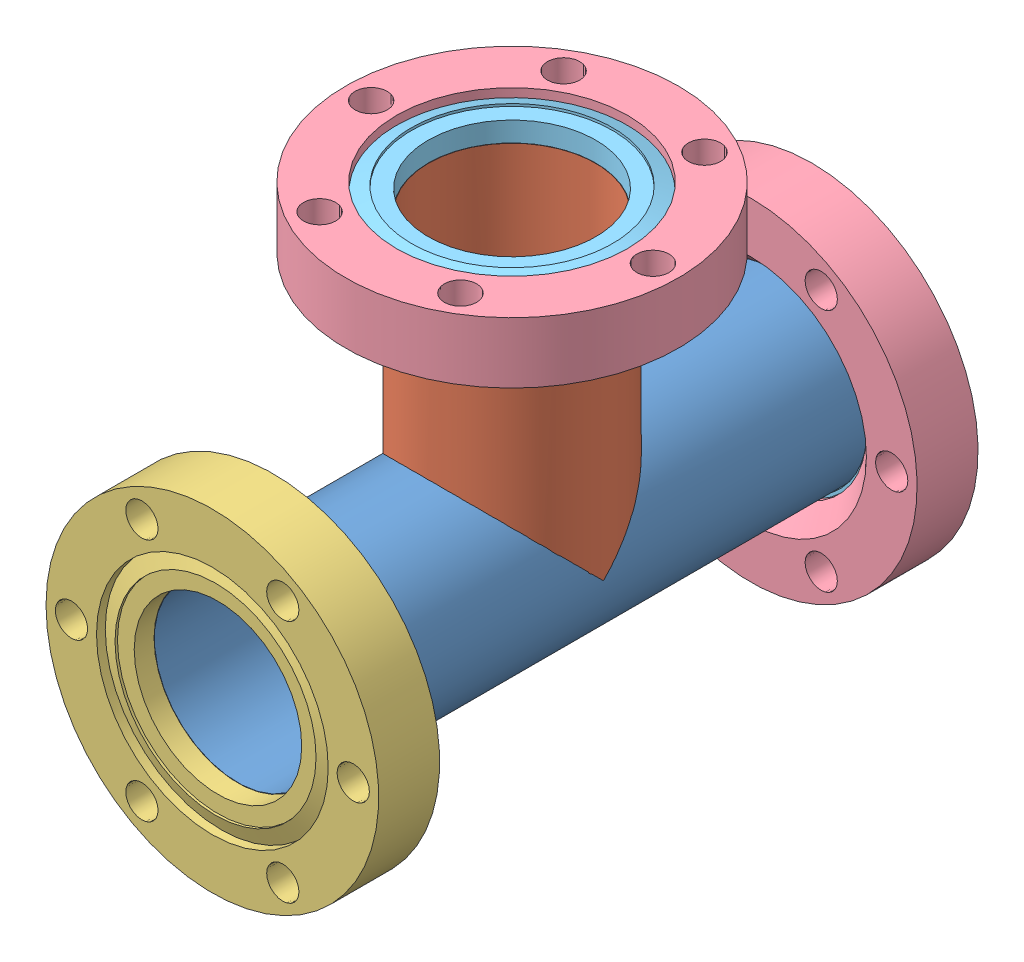
SolidWorks assembly 2D MOT tee_404002, configuration Default. Lengths in mm.
Overall size (69.34 97.13 124.92).
9 component instances, 5 part files, 0 mates.
Components (placement in the parent):
- 404002 P5_404002-001-1: 404002 P5_404002-001 [Default] at origin size (38.1 38.1 114.3)
- 404002 P6_404002-002-1: 404002 P6_404002-002 [Default] at (0 0 57.15) x (-1 0 0) z (0 1 0) size (38.1 38.1 58.86)
- 404002 P4_110014 (2.75 X 1.5 NR)_1-1: 404002 P4_110014 (2.75 X 1.5 NR)_1 [Default] at (0 0 113.2586) x (0 0 1) z (-1 0 0) size (12.7 69.34 69.34)
- 404002 P2_100014 (2.75 X 1.5 R)-1: 404002 P2_100014 (2.75 X 1.5 R) [Default] at (0 62.4586 57.15) x (0 -1 0) z (1 0 0) size (12.7 69.34 69.34)
  - 404002 P3_100014 (2.75 X 1.5 REC)-1: 404002 P3_100014 (2.75 X 1.5 REC) [Default] at origin size (12.7 69.34 69.34)
  - 404002 P1_100014 (2.75 X 1.5 INS)-1: 404002 P1_100014 (2.75 X 1.5 INS) [Default] at (1.17 0 0) x (1 0 0) z (0 0.994423 -0.105464) size (6.96 48.1 48.1)
- 404002 P2_100014 (2.75 X 1.5 R)-2: 404002 P2_100014 (2.75 X 1.5 R) [Default] at (0 0 -5.3086) x (0 0 1) z (-1 0 0) size (12.7 69.34 69.34)
  - 404002 P3_100014 (2.75 X 1.5 REC)-1: 404002 P3_100014 (2.75 X 1.5 REC) [Default] at origin size (12.7 69.34 69.34)
  - 404002 P1_100014 (2.75 X 1.5 INS)-1: 404002 P1_100014 (2.75 X 1.5 INS) [Default] at (1.17 0 0) x (1 0 0) z (0 0.994423 -0.105464) size (6.96 48.1 48.1)
